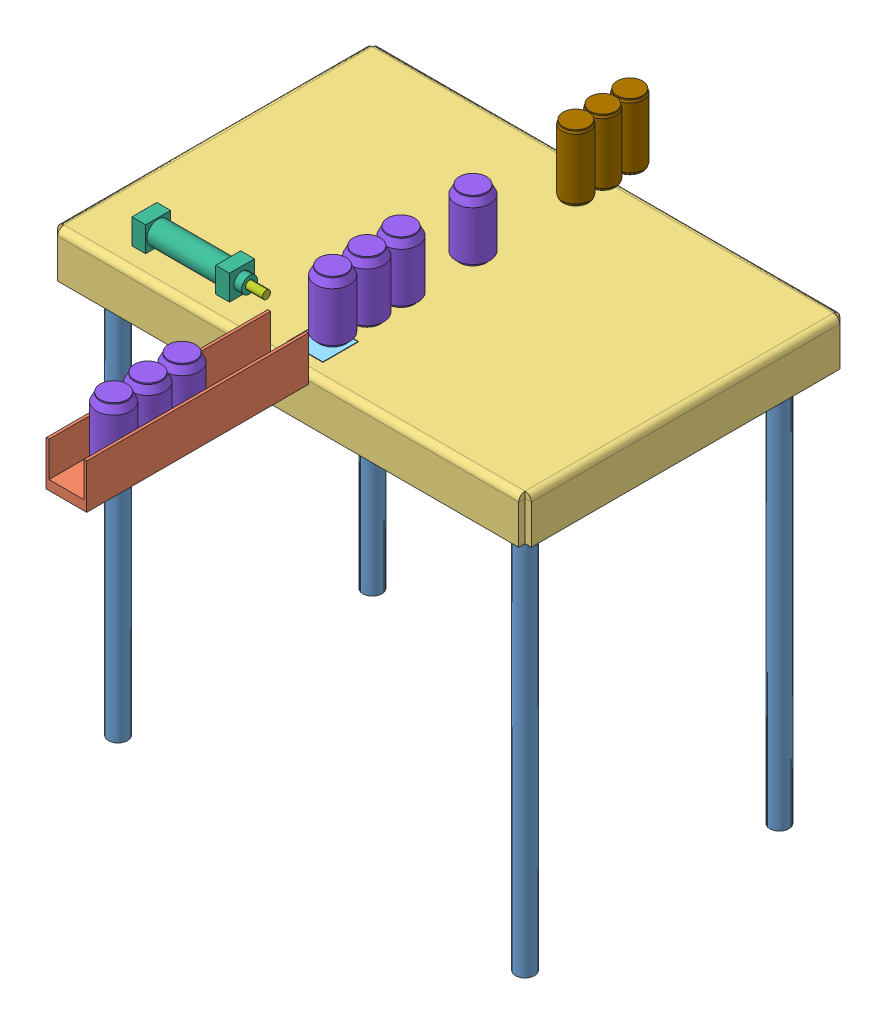
SolidWorks assembly Full Assembly, configuration Default. Lengths in mm.
Overall size (946.15 1065.21 1163.26).
18 component instances, 9 part files, 46 mates.
Components (placement in the parent):
- M37 Metal Table-1: M37 Metal Table [Default] at (-122.75 340.8931 1031.9817) size (914.4 863.6 609.6)
- Goose Output-1: Goose Output [Default] at (293.9688 417.0931 1047.8567) size (80.96 88.9 442.73)
- Table Topper-1: Table Topper [Default] at (-125.925 345.3431 1035.1567) size (946.15 90.8 641.35)
- Load Cell Assembly-1: Load Cell Assembly [Default] at (309.0555 378.227 899.7114) size (69.85 26.2 103.99)
  - Load Cell and Brace-1: Load Cell and Brace [Default] at (-9.1055 31.7162 92.7424) size (69 14.2 83)
  - scalePlate_v2_234-1: scalePlate_v2_234 [Default] at (-9.5305 57.9162 113.7283) x (0 0 -1) z (-1 0 0) size (69.85 12 69.85)
- Cylinder-1: Cylinder [Default] at (-22.0508 486.1431 953.5147) x (0 0 1) z (1 0 0) size (50 50 210)
- Rod-1: Rod [Default] at (221.9492 461.1431 978.5147) x (0 0.637822 -0.770184) z (0 0.770184 0.637822) size (16 134 16)
- can355mL-1: can355mL [Default] at (334.45 436.1431 822.479) x (0.989638 0 0.143588) z (-0.143588 0 0.989638) size (68.26 122.24 68.26)
- can355mL-2: can355mL [Default] at (334.45 436.1431 959.004) x (0.731363 0 -0.681988) z (0.681988 0 0.731363) size (68.26 122.24 68.26)
- can355mL-3: can355mL [Default] at (334.45 436.1431 890.7415) x (0.144294 0 -0.989535) z (0.989535 0 0.144294) size (68.26 122.24 68.26)
- can250mL-1: can250mL [Default] at (334.45 436.1431 473.4181) x (0.051367 0 -0.99868) z (0.99868 0 0.051367) size (53.98 131.76 53.98)
- can250mL-2: can250mL [Default] at (334.45 436.1431 419.4431) x (0.934155 0 -0.356866) z (0.356866 0 0.934155) size (53.98 131.76 53.98)
- can250mL-3: can250mL [Default] at (334.45 436.1431 365.4681) x (0.679338 0 0.733825) z (-0.733825 0 0.679338) size (53.98 131.76 53.98)
- can355mL-4: can355mL [Default] at (334.45 436.1431 1259.8293) x (-0.654942 0 -0.755679) z (0.755679 0 -0.654942) size (68.26 122.24 68.26)
- can355mL-5: can355mL [Default] at (334.45 436.1431 1328.0918) x (-0.915594 0 0.402104) z (-0.402104 0 -0.915594) size (68.26 122.24 68.26)
- can355mL-6: can355mL [Default] at (334.45 436.1431 1396.3543) x (0.268992 0 -0.963143) z (0.963143 0 0.268992) size (68.26 122.24 68.26)
- can355mL-7: can355mL [Default] at (334.45 436.1431 678.8486) x (-0.857287 0 0.514838) z (-0.514838 0 -0.857287) size (68.26 122.24 68.26)
Mates (geometry in assembly coordinates):
- Width1: width aligned: plane of M37 Metal Table-1 through (791.65 366.2931 1031.9817) normal (1 0 0); plane of M37 Metal Table-1 through (-122.75 366.2931 1031.9817) normal (-1 0 0); plane of Table Topper-1 through (807.525 423.4431 1035.1567) normal (1 0 0); plane of Table Topper-1 through (-138.625 423.4431 1035.1567) normal (-1 0 0)
- Width2: width aligned: plane of M37 Metal Table-1 through (-122.75 366.2931 1031.9817) normal (0 0 1); plane of M37 Metal Table-1 through (-122.75 366.2931 422.3817) normal (0 0 -1); plane of Table Topper-1 through (-125.925 423.4431 1047.8567) normal (0 0 1); plane of Table Topper-1 through (-125.925 423.4431 406.5067) normal (0 0 -1)
- Distance1: distance = 863.6 mm aligned: plane of M37 Metal Table-1 through (-122.75 -446.5069 1031.9817) normal (0 -1 0); plane of Goose Output-1 through (374.9313 417.0931 1490.5914) normal (0 -1 0)
- LimitDistance1: limit distance = 432.5938 mm aligned: plane of Goose Output-1 through (374.9313 505.9931 1490.5914) normal (1 0 0); plane of Table Topper-1 through (807.525 423.4431 1035.1567) normal (1 0 0)
- LimitDistance2: limit distance = 432.5938 mm aligned: plane of Table Topper-1 through (-138.625 423.4431 1035.1567) normal (-1 0 0); plane of Goose Output-1 through (293.9688 417.0931 1490.5914) normal (-1 0 0)
- Parallel1: parallel aligned: plane of Goose Output-1 through (299.525 436.1431 1490.5914) normal (0 1 0); plane of Table Topper-1 through (-125.925 436.1431 1035.1567) normal (0 1 0)
- Coincident5: coincident aligned: plane of Goose Output-1 through (299.525 436.1431 1490.5914) normal (0 1 0); plane of Table Topper-1 through (-125.925 436.1431 1035.1567) normal (0 1 0)
- Coincident7: coincident aligned: plane of Table Topper-1 through (-125.925 436.1431 1035.1567) normal (0 1 0); plane of Load Cell Assembly-1/scalePlate_v2_234-1 through (299.525 436.1431 1013.4397) normal (0 1 0)
- Concentric1: concentric anti-aligned: cylinder of Cylinder-1 through (187.9492 461.1431 978.5147) axis (-1 0 0) radius 16; cylinder of Rod-1 through (87.9492 461.1431 978.5147) axis (1 0 0) radius 8
- LimitDistance3: limit distance = 34 mm aligned: plane of Rod-1 through (221.9492 461.1431 978.5147) normal (1 0 0); plane of Cylinder-1 through (187.9492 461.1431 978.5147) normal (1 0 0)
- Parallel2: parallel anti-aligned: plane of Table Topper-1 through (-125.925 423.4431 1047.8567) normal (0 0 1); plane of Cylinder-1 through (172.9492 486.1431 953.5147) normal (0 0 -1)
- Coincident9: coincident anti-aligned: plane of Table Topper-1 through (-125.925 436.1431 1035.1567) normal (0 1 0); plane of Cylinder-1 through (5.4492 436.1431 953.5147) normal (0 -1 0)
- Width3: width anti-aligned: plane of Goose Output-1 through (374.9313 505.9931 1490.5914) normal (1 0 0); plane of Goose Output-1 through (293.9688 417.0931 1490.5914) normal (-1 0 0); plane of Load Cell Assembly-1/scalePlate_v2_234-1 through (299.525 432.1431 1013.4397) normal (-1 0 0); plane of Load Cell Assembly-1/scalePlate_v2_234-1 through (369.375 432.1431 1013.4397) normal (1 0 0)
- Width4: width anti-aligned: plane of Cylinder-1 through (172.9492 486.1431 953.5147) normal (0 0 -1); plane of Cylinder-1 through (172.9492 486.1431 1003.5147) normal (0 0 1); plane of Load Cell Assembly-1/scalePlate_v2_234-1 through (299.525 432.1431 1013.4397) normal (0 0 1); plane of Load Cell Assembly-1/scalePlate_v2_234-1 through (299.525 432.1431 943.5897) normal (0 0 -1)
- Width5: width anti-aligned: plane of Table Topper-1 through (807.525 423.4431 1035.1567) normal (1 0 0); plane of Table Topper-1 through (-138.625 423.4431 1035.1567) normal (-1 0 0); plane of Load Cell Assembly-1/scalePlate_v2_234-1 through (299.525 432.1431 1013.4397) normal (-1 0 0); plane of Load Cell Assembly-1/scalePlate_v2_234-1 through (369.375 432.1431 1013.4397) normal (1 0 0)
- Coincident11: coincident anti-aligned: plane of Table Topper-1 through (-125.925 436.1431 1035.1567) normal (0 1 0); plane of can250mL-1 through (335.7548 436.1431 448.0516) normal (0 -1 0)
- Coincident18: coincident anti-aligned: plane of Table Topper-1 through (-125.925 436.1431 1035.1567) normal (0 1 0); plane of can355mL-2 through (354.1877 436.1431 940.5988) normal (0 -1 0)
- Coincident19: coincident anti-aligned: plane of Table Topper-1 through (-125.925 436.1431 1035.1567) normal (0 1 0); plane of can355mL-3 through (338.3442 436.1431 864.0364) normal (0 -1 0)
- Tangent5: tangent anti-aligned: cylinder of can355mL-2 through (334.45 436.1431 959.004) axis (0 -1 0) radius 34.1313; cylinder of can355mL-3 through (334.45 436.1431 890.7415) axis (0 -1 0) radius 34.1313
- Width6: width: plane of Goose Output-1 through (299.525 505.9931 1490.5914) normal (1 0 0); plane of Goose Output-1 through (369.375 436.1431 1490.5914) normal (-1 0 0); cylinder of can250mL-1 through (334.45 436.1431 473.4181) axis (0 -1 0) radius 26.9875
- Width8: width: plane of Goose Output-1 through (369.375 436.1431 1490.5914) normal (-1 0 0); plane of Goose Output-1 through (299.525 505.9931 1490.5914) normal (1 0 0); cylinder of can355mL-2 through (334.45 436.1431 959.004) axis (0 -1 0) radius 34.1313
- Width10: width: plane of Goose Output-1 through (299.525 505.9931 1490.5914) normal (1 0 0); plane of Goose Output-1 through (369.375 436.1431 1490.5914) normal (-1 0 0); cylinder of can355mL-3 through (334.45 436.1431 890.7415) axis (0 -1 0) radius 34.1313
- Coincident20: coincident anti-aligned: plane of Table Topper-1 through (-125.925 436.1431 1035.1567) normal (0 1 0); plane of can250mL-2 through (358.1776 436.1431 410.3787) normal (0 -1 0)
- Coincident21: coincident anti-aligned: plane of Table Topper-1 through (-125.925 436.1431 1035.1567) normal (0 1 0); plane of can250mL-3 through (351.7052 436.1431 384.1073) normal (0 -1 0)
- Tangent6: tangent anti-aligned: cylinder of can250mL-1 through (334.45 436.1431 473.4181) axis (0 -1 0) radius 26.9875; cylinder of can250mL-2 through (334.45 436.1431 419.4431) axis (0 -1 0) radius 26.9875
- Tangent7: tangent anti-aligned: cylinder of can250mL-2 through (334.45 436.1431 419.4431) axis (0 -1 0) radius 26.9875; cylinder of can250mL-3 through (334.45 436.1431 365.4681) axis (0 -1 0) radius 26.9875
- Width11: width: plane of Goose Output-1 through (299.525 505.9931 1490.5914) normal (1 0 0); plane of Goose Output-1 through (369.375 436.1431 1490.5914) normal (-1 0 0); cylinder of can250mL-2 through (334.45 436.1431 419.4431) axis (0 -1 0) radius 26.9875
- Width12: width: plane of Goose Output-1 through (299.525 505.9931 1490.5914) normal (1 0 0); plane of Goose Output-1 through (369.375 436.1431 1490.5914) normal (-1 0 0); cylinder of can250mL-3 through (334.45 436.1431 365.4681) axis (0 -1 0) radius 26.9875
- Coincident22: coincident anti-aligned: plane of Goose Output-1 through (293.9688 417.0931 1047.8567) normal (0 0 -1); plane of Table Topper-1 through (-125.925 423.4431 1047.8567) normal (0 0 1)
- Width14: width aligned: plane of Table Topper-1 through (370.391 345.3431 1014.4557) normal (-1 0 0); plane of Load Cell Assembly-1/scalePlate_v2_234-1 through (298.509 345.3431 1014.4557) normal (1 0 0); plane of Table Topper-1 through (299.525 432.1431 1013.4397) normal (-1 0 0); plane of Load Cell Assembly-1/scalePlate_v2_234-1 through (369.375 432.1431 1013.4397) normal (1 0 0)
- Width15: width anti-aligned: plane of Table Topper-1 through (298.509 345.3431 1014.4557) normal (0 0 -1); plane of Load Cell Assembly-1/scalePlate_v2_234-1 through (298.509 345.3431 942.5737) normal (0 0 1); plane of Table Topper-1 through (299.525 432.1431 1013.4397) normal (0 0 1); plane of Load Cell Assembly-1/scalePlate_v2_234-1 through (299.525 432.1431 943.5897) normal (0 0 -1)
- Tangent8: tangent anti-aligned: cylinder of can355mL-5 through (334.45 436.1431 1328.0918) axis (0 -1 0) radius 34.1313; cylinder of can355mL-6 through (334.45 436.1431 1396.3543) axis (0 -1 0) radius 34.1313
- Tangent9: tangent anti-aligned: cylinder of can355mL-4 through (334.45 436.1431 1259.8293) axis (0 -1 0) radius 34.1313; cylinder of can355mL-5 through (334.45 436.1431 1328.0918) axis (0 -1 0) radius 34.1313
- Coincident28: coincident aligned: plane of can355mL-5 through (309.7405 436.1431 1338.9436) normal (0 -1 0); plane of can355mL-6 through (341.7095 436.1431 1370.3615) normal (0 -1 0)
- Coincident29: coincident aligned: plane of can355mL-4 through (316.7748 436.1431 1239.4354) normal (0 -1 0); plane of can355mL-5 through (309.7405 436.1431 1338.9436) normal (0 -1 0)
- Width16: width: plane of Goose Output-1 through (369.375 436.1431 1490.5914) normal (-1 0 0); plane of can355mL-6 through (299.525 505.9931 1490.5914) normal (1 0 0); cylinder of Goose Output-1 through (334.45 436.1431 1396.3543) axis (0 -1 0) radius 34.1313
- Width17: width: plane of Goose Output-1 through (369.375 436.1431 1490.5914) normal (-1 0 0); plane of can355mL-4 through (299.525 505.9931 1490.5914) normal (1 0 0); cylinder of Goose Output-1 through (334.45 436.1431 1259.8293) axis (0 -1 0) radius 34.1313
- Width18: width: plane of Goose Output-1 through (369.375 436.1431 1490.5914) normal (-1 0 0); plane of can355mL-5 through (299.525 505.9931 1490.5914) normal (1 0 0); cylinder of Goose Output-1 through (334.45 436.1431 1328.0918) axis (0 -1 0) radius 34.1313
- Coincident31: coincident anti-aligned: plane of Table Topper-1 through (-125.925 436.1431 1035.1567) normal (0 1 0); plane of can355mL-7 through (311.314 436.1431 692.7428) normal (0 -1 0)
- Width19: width: plane of Goose Output-1 through (369.375 436.1431 1490.5914) normal (-1 0 0); plane of can355mL-7 through (299.525 505.9931 1490.5914) normal (1 0 0); cylinder of Goose Output-1 through (334.45 436.1431 678.8486) axis (0 -1 0) radius 34.1313
- Coincident32: coincident anti-aligned: plane of Table Topper-1 through (-125.925 436.1431 1035.1567) normal (0 1 0); plane of can355mL-6 through (341.7095 436.1431 1370.3615) normal (0 -1 0)
- Coincident33: coincident anti-aligned: plane of Table Topper-1 through (-125.925 436.1431 1035.1567) normal (0 1 0); plane of can355mL-1 through (361.1579 436.1431 826.3541) normal (0 -1 0)
- Tangent13: tangent anti-aligned: cylinder of can355mL-1 through (334.45 436.1431 822.479) axis (0 -1 0) radius 34.1313; cylinder of can355mL-3 through (334.45 436.1431 890.7415) axis (0 -1 0) radius 34.1313
- Width20: width: plane of Goose Output-1 through (299.525 505.9931 1490.5914) normal (1 0 0); plane of can355mL-1 through (369.375 436.1431 1490.5914) normal (-1 0 0); cylinder of Goose Output-1 through (334.45 436.1431 822.479) axis (0 -1 0) radius 34.1313
- LimitDistance5: limit distance = 60.1059 mm: line of Goose Output-1 through (369.375 436.1431 1490.5914) axis (-1 0 0); cylinder of can355mL-6 through (334.45 436.1431 1396.3543) axis (0 -1 0) radius 34.1313
- LimitDistance10: limit distance = 75.3679 mm: cylinder of can355mL-7 through (334.45 436.1431 678.8486) axis (0 -1 0) radius 34.1313; cylinder of can355mL-1 through (334.45 436.1431 822.479) axis (0 -1 0) radius 34.1313
